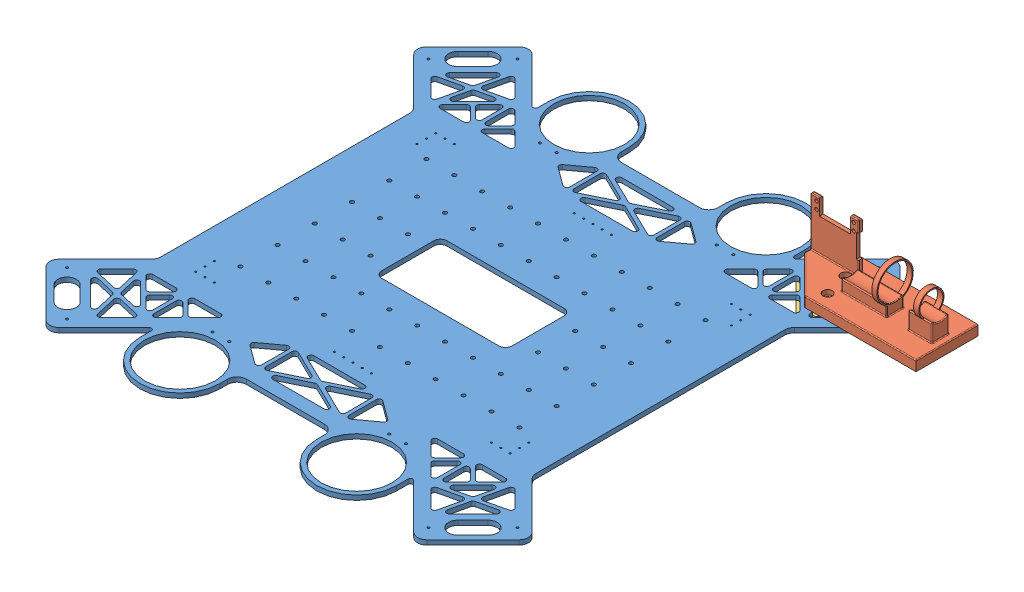
SolidWorks assembly MS-SA-0012i Old (current) bellypan Torpedo Mounting, configuration Default. Lengths in mm.
Overall size (728.7 99.15 668.02).
3 component instances, 3 part files, 1 mates.
Components (placement in the parent):
- MS-P-0008-Frame, Base Plate [DEFUNCT]-1: MS-P-0008-Frame, Base Plate [DEFUNCT] [Waterjet] at origin size (653.22 6.35 668.02)
- MS-P-0108 Torpedo Mechanism Mount-1: MS-P-0108 Torpedo Mechanism Mount [Default] at (327.0228 55.888 -245.2225) x (0 1 0) z (0 0 -1) size (79.67 203.87 84.58)
- MS-P-0107 Torpedo Mounting Plate-1: MS-P-0107 Torpedo Mounting Plate [Default] at (-0.4513 -12.7 1.0502) x (-0.002894 0 -0.999996) z (0 1 0) size (113.15 113.15 12.7)
Mates (geometry in assembly coordinates):
- Coincident2: coincident aligned: plane of MS-P-0008-Frame, Base Plate [DEFUNCT]-1 through (0 0 0) normal (0 1 0); plane of Part4-1 through (-0.4513 0 1.0502) normal (0 1 0)
